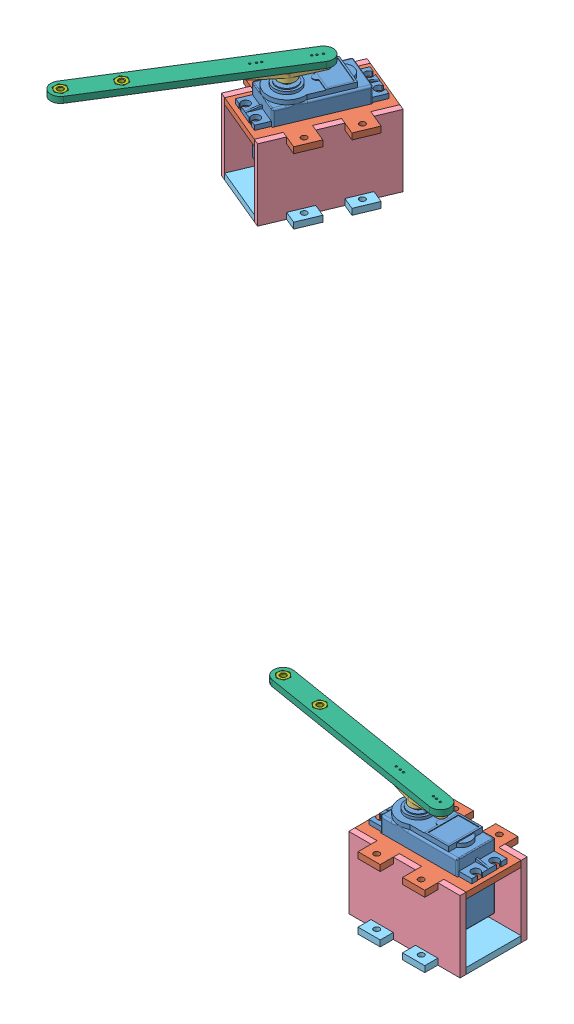
SolidWorks assembly Assem3, configuration Default. Lengths in mm.
Overall size (181.12 338.48 137.88).
20 component instances, 7 part files, 1 mates.
Components (placement in the parent):
- Worm Segment-1: Worm Segment [Default] at (44.0887 40.7782 66.1593) size (129.99 59.38 48.8)
  - Servo-1: Servo [Predeterminado] at (16.062 27.2827 43.9827) size (53.82 44.84 19.95)
  - Servo Case Front-1: Servo Case Front [Default] at (-13.078 34.2977 43.9827) x (1 0 0) z (0 1 0) size (58.28 48.8 3.17)
  - Servo Horn-1: Servo Horn [Default] at (5.812 53.8327 43.9827) x (-0.163066 0 0.986615) z (-0.986615 0 -0.163066) size (9.1 5 34)
  - Servo Case Side-1: Servo Case Side [Default] at (-13.078 18.7977 26.4077) size (58.28 37.35 3.17)
  - Servo Case Side-2: Servo Case Side [Default] at (-13.078 18.7977 58.3827) size (58.28 37.35 3.17)
  - Servo Case Back-1: Servo Case Back [Default] at (-13.078 3.2977 43.9827) x (1 0 0) z (0 -1 0) size (58.28 48.8 3.17)
  - Arm-1: Arm [Default] at (-79.0369 59.5077 29.959) x (0.986615 0 0.163066) z (0 -1 0) size (110 10 3.17)
  - M3 Nut-1: M3 Nut [Default] at (-79.0329 58.3077 29.9348) x (0.634527 0 -0.772901) z (0 -1 0) size (5.5 6.35 2.4)
  - M3 Nut-2: M3 Nut [Default] at (-56.0349 58.3077 33.7359) x (0.986615 0 0.163066) z (0 1 0) size (5.5 6.35 2.4)
- Worm Segment-2: Worm Segment [Default] at (-77.2276 319.878 83.2099) x (0.385376 0 -0.92276) z (0.92276 0 0.385376) size (129.99 59.38 48.8)
  - Servo-1: Servo [Predeterminado] at (16.062 27.2827 43.9827) size (53.82 44.84 19.95)
  - Servo Case Front-1: Servo Case Front [Default] at (-13.078 34.2977 43.9827) x (1 0 0) z (0 1 0) size (58.28 48.8 3.17)
  - Servo Horn-1: Servo Horn [Default] at (5.812 53.8327 43.9827) x (-0.163066 0 0.986615) z (-0.986615 0 -0.163066) size (9.1 5 34)
  - Servo Case Side-1: Servo Case Side [Default] at (-13.078 18.7977 26.4077) size (58.28 37.35 3.17)
  - Servo Case Side-2: Servo Case Side [Default] at (-13.078 18.7977 58.3827) size (58.28 37.35 3.17)
  - Servo Case Back-1: Servo Case Back [Default] at (-13.078 3.2977 43.9827) x (1 0 0) z (0 -1 0) size (58.28 48.8 3.17)
  - Arm-1: Arm [Default] at (-79.0369 59.5077 29.959) x (0.986615 0 0.163066) z (0 -1 0) size (110 10 3.17)
  - M3 Nut-1: M3 Nut [Default] at (-79.0329 58.3077 29.9348) x (0.634527 0 -0.772901) z (0 -1 0) size (5.5 6.35 2.4)
  - M3 Nut-2: M3 Nut [Default] at (-56.0349 58.3077 33.7359) x (0.986615 0 0.163066) z (0 1 0) size (5.5 6.35 2.4)
Mates (geometry in assembly coordinates):
- Concentric1: concentric aligned: circle of Worm Segment-1/M3 Nut-1; circle of Worm Segment-2/Servo Case Back-1
